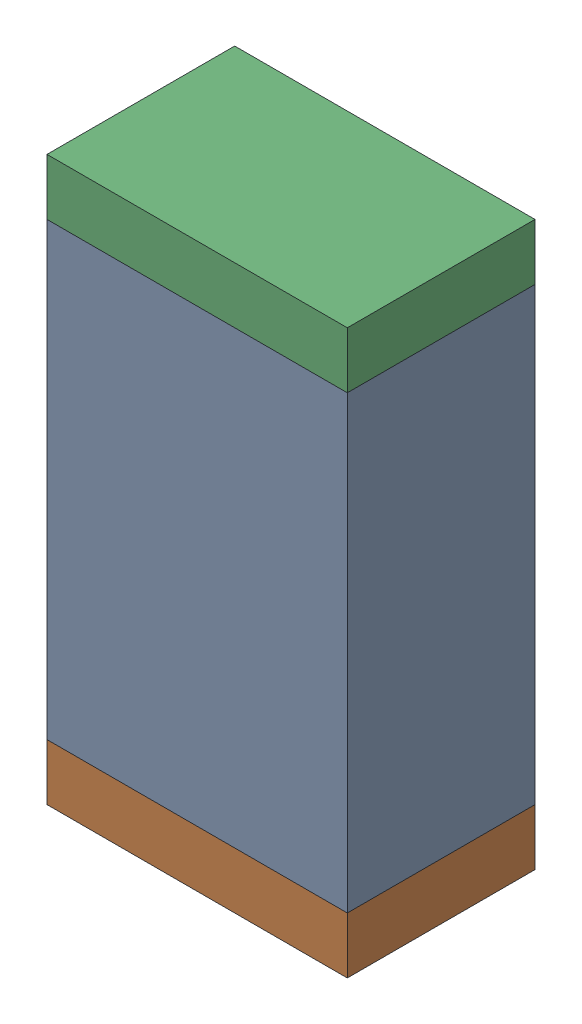
SolidWorks assembly R13, configuration Default. Lengths in mm.
Overall size (0.8 1.5 0.5).
6 component instances, 2 part files, 0 mates.
Components (placement in the parent):
- 810156976-1: 810156976 [Default] at (133.35 39.3 0) size (0.8 1.2 0.5)
  - Extruded_6-1: Extruded_6 [Default] at origin size (0.8 1.2 0.5)
- 810156592-1: 810156592 [Default] at (133.35 38.625 0) size (0.8 0.15 0.5)
  - Extruded_7-1: Extruded_7 [Default] at origin size (0.8 0.15 0.5)
- 810156592-2: 810156592 [Default] at (133.35 39.975 0) size (0.8 0.15 0.5)
  - Extruded_7-1: Extruded_7 [Default] at origin size (0.8 0.15 0.5)
